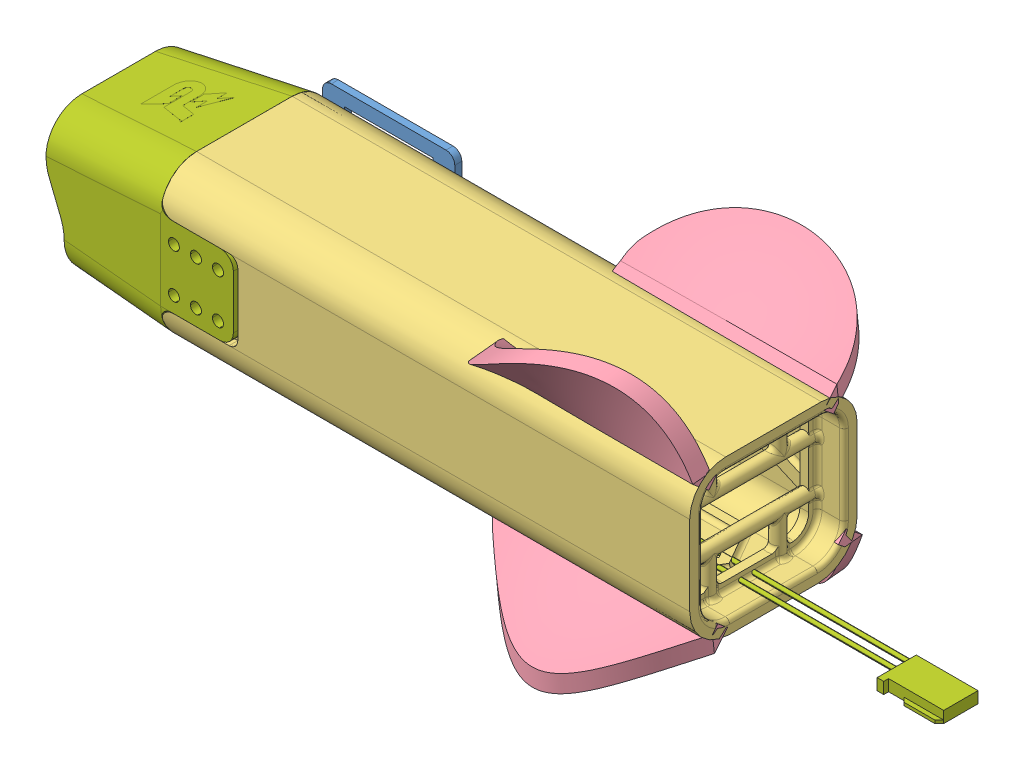
SolidWorks assembly 装配示意, configuration 默认. Lengths in mm.
Overall size (193.7 75.54 74.98).
23 component instances, 7 part files, 12 mates.
Components (placement in the parent):
- PCB&电流针-1: PCB&电流针 [默认] at (-94.1724 -135.9674 -52.4123) x (0 -1 0) z (0 0 -1) size (35.32 30 10)
  - Charging_PCB版型_for_AD21-1: Charging_PCB版型_for_AD21 [默认] at (-152.1489 21.7341 -0.8) size (35.32 30 1.6)
  - 电流针_2mm直径10mm长-1: 电流针_2mm直径10mm长 [默认] at (-137.7644 25.2341 1.3) x (0.98041 0.196968 0) z (-0.196968 0.98041 0) size (2 10 2)
  - 电流针_2mm直径10mm长-2: 电流针_2mm直径10mm长 [默认] at (-127.7644 25.2341 1.3) x (1 0 0) z (0 1 0) size (2 10 2)
- 飞镖带尾翼-1: 飞镖带尾翼 [默认] at (-0.5523 -25.3719 -33.8909) size (122.83 75.54 74.98)
  - Tropedo_Body_V1-1: Tropedo_Body_V1 [默认] at (-106.8542 4.5498 -0.0001) size (120 35.32 38.34)
  - 17右上螺旋翼-1: 17右上螺旋翼 [默认] at (-6.8542 38.1319 18.8007) x (0 0.104528 -0.994522) z (1 0 0) size (23.15 26.77 62.83)
  - 17右上螺旋翼-2: 17右上螺旋翼 [默认] at (-6.8542 9.1481 -20.6645) x (0 -0.104528 0.994522) z (1 0 0) size (23.15 26.77 62.83)
  - 17右上螺旋翼-3: 17右上螺旋翼 [默认] at (-6.8542 2.0359 13.35) x (0 0.994522 0.104528) z (1 0 0) size (23.15 26.77 62.83)
  - 17右上螺旋翼-4: 17右上螺旋翼 [默认] at (-6.8542 42.0551 -14.3247) x (0 -0.994522 -0.104528) z (1 0 0) size (23.15 26.77 62.83)
- Magnetic_PCB_with_SDM-nut_with_thickness-1: Magnetic_PCB_with_SDM-nut_with_thickness [默认] at (16.2187 -47.4526 -45.1849) size (24.64 24.01 5.9)
  - Magnetic_PCB_with_SDM-nut_with_thickness-1: Magnetic_PCB_with_SDM-nut_with_thickness [默认] at (-126.959 42.921 -25.2644) size (24.01 24.01 4)
  - 贴片螺母SMTSO-M2.5-3ET-1: 贴片螺母SMTSO-M2.5-3ET [默认] at (-140.6253 49.2542 0.9) x (-0.923728 -0.383049 0) z (0.383049 -0.923728 0) size (5.56 4.53 5.56)
  - 贴片螺母SMTSO-M2.5-3ET-2: 贴片螺母SMTSO-M2.5-3ET [默认] at (-130.6253 49.2542 0.9) x (-0.923728 -0.383049 0) z (0.383049 -0.923728 0) size (5.56 4.53 5.56)
  - 贴片螺母SMTSO-M2.5-3ET-3: 贴片螺母SMTSO-M2.5-3ET [默认] at (-140.6253 39.2542 0.9) x (-0.923728 -0.383049 0) z (0.383049 -0.923728 0) size (5.56 4.53 5.56)
  - 贴片螺母SMTSO-M2.5-3ET-4: 贴片螺母SMTSO-M2.5-3ET [默认] at (-130.6253 39.2542 0.9) x (-0.923728 -0.383049 0) z (0.383049 -0.923728 0) size (5.56 4.53 5.56)
- Magnetic_PCB_with_SDM-nut_with_thickness-2: Magnetic_PCB_with_SDM-nut_with_thickness [默认] at (16.2187 41.0558 -22.5971) x (1 0 0) z (0 0 -1) size (24.64 24.01 5.9)
  - Magnetic_PCB_with_SDM-nut_with_thickness-1: Magnetic_PCB_with_SDM-nut_with_thickness [默认] at (-126.959 42.921 -25.2644) size (24.01 24.01 4)
  - 贴片螺母SMTSO-M2.5-3ET-1: 贴片螺母SMTSO-M2.5-3ET [默认] at (-140.6253 49.2542 0.9) x (-0.923728 -0.383049 0) z (0.383049 -0.923728 0) size (5.56 4.53 5.56)
  - 贴片螺母SMTSO-M2.5-3ET-2: 贴片螺母SMTSO-M2.5-3ET [默认] at (-130.6253 49.2542 0.9) x (-0.923728 -0.383049 0) z (0.383049 -0.923728 0) size (5.56 4.53 5.56)
  - 贴片螺母SMTSO-M2.5-3ET-3: 贴片螺母SMTSO-M2.5-3ET [默认] at (-140.6253 39.2542 0.9) x (-0.923728 -0.383049 0) z (0.383049 -0.923728 0) size (5.56 4.53 5.56)
  - 贴片螺母SMTSO-M2.5-3ET-4: 贴片螺母SMTSO-M2.5-3ET [默认] at (-130.6253 39.2542 0.9) x (-0.923728 -0.383049 0) z (0.383049 -0.923728 0) size (5.56 4.53 5.56)
- RoboMaster飞镖触发装置-1: RoboMaster飞镖触发装置 [默认] at (-115.9065 16.1861 -33.891) x (0 0 -1) z (0 1 0) size (38.05 193.7 35.39)
Mates (geometry in assembly coordinates):
- 重合3: coincident anti-aligned: plane of 飞镖带尾翼-1/Tropedo_Body_V1-1 through (-121.4065 -20.8222 -45.8849) normal (0 0 1); plane of Magnetic_PCB_with_SDM-nut_with_thickness-1/Magnetic_PCB_with_SDM-nut_with_thickness-1 through (-127.4065 -13.1984 -45.8849) normal (0 0 -1)
- 同心5: concentric anti-aligned: cylinder of 飞镖带尾翼-1/Tropedo_Body_V1-1 through (-124.4065 1.8016 -52.8854) axis (0 0 1) radius 1.25; cylinder of Magnetic_PCB_with_SDM-nut_with_thickness-1/贴片螺母SMTSO-M2.5-3ET-1 through (-124.4065 1.8016 -45.8149) axis (0 0 -1) radius 1.025
- 同心6: concentric anti-aligned: cylinder of 飞镖带尾翼-1/Tropedo_Body_V1-1 through (-114.4065 -8.1984 -52.8854) axis (0 0 1) radius 1.25; cylinder of Magnetic_PCB_with_SDM-nut_with_thickness-1/贴片螺母SMTSO-M2.5-3ET-4 through (-114.4065 -8.1984 -45.8149) axis (0 0 -1) radius 1.025
- 重合5: coincident anti-aligned: plane of 飞镖带尾翼-1/Tropedo_Body_V1-1 through (-121.4065 -20.8222 -21.8971) normal (0 0 -1); plane of Magnetic_PCB_with_SDM-nut_with_thickness-2/Magnetic_PCB_with_SDM-nut_with_thickness-1 through (-127.4065 6.8016 -21.8971) normal (0 0 1)
- 同心7: concentric aligned: cylinder of 飞镖带尾翼-1/Tropedo_Body_V1-1 through (-124.4065 1.8016 -52.8854) axis (0 0 1) radius 1.25; cylinder of Magnetic_PCB_with_SDM-nut_with_thickness-2/贴片螺母SMTSO-M2.5-3ET-3 through (-124.4065 1.8016 -21.9671) axis (0 0 1) radius 1.025
- 同心8: concentric aligned: cylinder of 飞镖带尾翼-1/Tropedo_Body_V1-1 through (-114.4065 -8.1984 -52.8854) axis (0 0 1) radius 1.25; cylinder of Magnetic_PCB_with_SDM-nut_with_thickness-2/贴片螺母SMTSO-M2.5-3ET-2 through (-114.4065 -8.1984 -21.9671) axis (0 0 1) radius 1.025
- 重合6: coincident aligned: plane of 飞镖带尾翼-1/Tropedo_Body_V1-1 through (-7.4065 6.297 -14.8971) normal (0 0 1); plane of RoboMaster飞镖触发装置-1 through (-115.9065 256.3016 -14.8971) normal (0 0 1)
- 重合7: coincident anti-aligned: plane of 飞镖带尾翼-1/Tropedo_Body_V1-1 through (-127.4065 6.1923 -23.1485) normal (-1 0 0); plane of RoboMaster飞镖触发装置-1 through (-127.4065 -22.8739 -8.891) normal (1 0 0)
- 同心9: concentric anti-aligned: cylinder of 飞镖带尾翼-1/Tropedo_Body_V1-1 through (-114.4065 1.8016 -52.8854) axis (0 0 1) radius 1.25; cylinder of RoboMaster飞镖触发装置-1 through (-114.4065 1.8016 -52.8849) axis (0 0 -1) radius 1.25
- 平行2: parallel anti-aligned: plane of PCB&电流针-1/Charging_PCB版型_for_AD21-1 through (-115.9065 16.1816 -51.6123) normal (0 0 1); plane of RoboMaster飞镖触发装置-1 through (-127.4065 256.3016 -52.8849) normal (0 0 -1)
- 重合13: coincident aligned: plane of PCB&电流针-1/Charging_PCB版型_for_AD21-1 through (-115.9065 14.4997 -53.2123) normal (0 1 0); plane of 飞镖带尾翼-1/Tropedo_Body_V1-1 through (-7.4065 14.4997 -44.7376) normal (0 1 0)
- 重合14: coincident anti-aligned: plane of PCB&电流针-1/Charging_PCB版型_for_AD21-1 through (-127.4065 16.1816 -53.2123) normal (-1 0 0); plane of RoboMaster飞镖触发装置-1 through (-127.4065 -22.8739 -8.891) normal (1 0 0)
